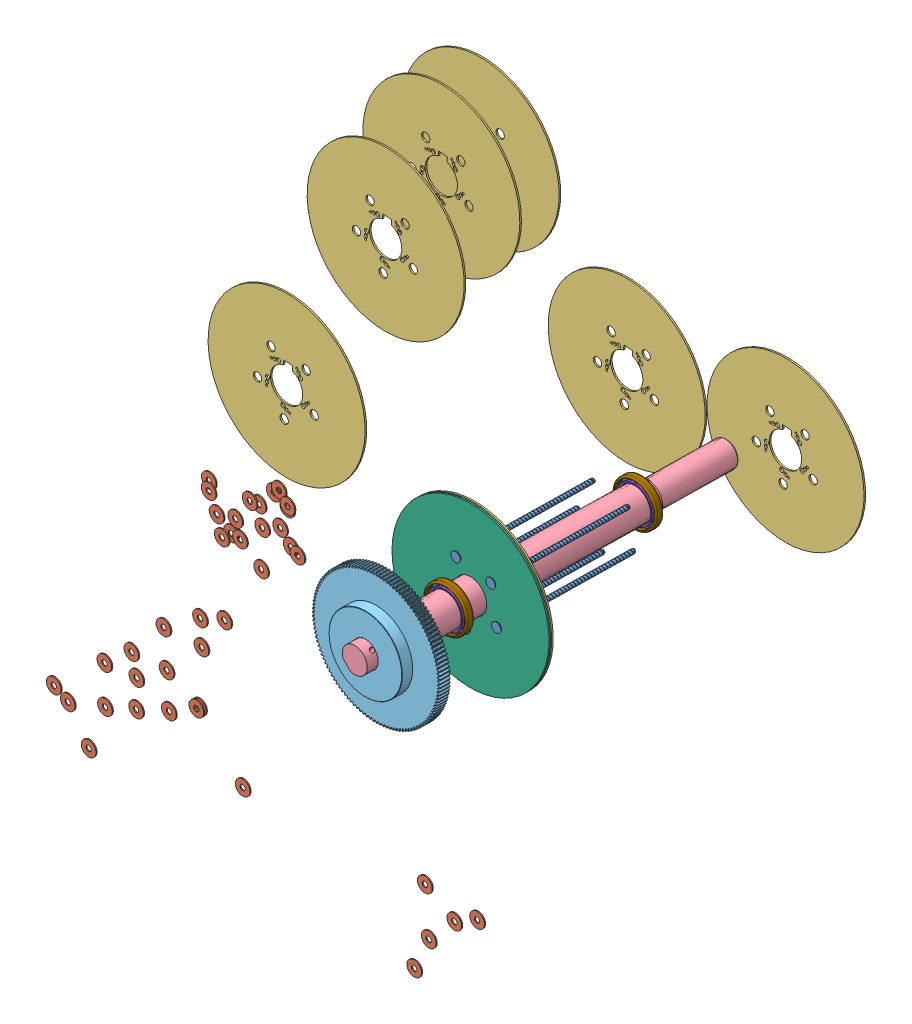
SolidWorks assembly Assemblage1, configuration Défaut. Lengths in mm.
Overall size (703.13 570.75 565.38).
85 component instances, 10 part files, 35 mates.
Components (placement in the parent):
- VISSE-1: VISSE [Défaut] at (277.8026 424.0876 541.0643) x (0.216681 0.976212 -0.007773) z (0.007976 -0.009732 -0.999921) size (9 9 132.7)
- rondelle-1: rondelle [Défaut] at (-148.9296 99.1333 254.7745) x (0.999968 0.00006 0.007975) z (-0.007976 0.009732 0.999921) size (14 14 1)
- VISSE-2: VISSE [Défaut] at (331.7467 416.4054 541.5693) x (-0.90111 0.433439 -0.011406) z (0.007976 -0.009732 -0.999921) size (9 9 132.7)
- VISSE-3: VISSE [Défaut] at (292.6231 454.3278 540.8882) x (-0.532627 -0.846341 0.003989) z (0.007976 -0.009732 -0.999921) size (9 9 132.7)
- VISSE-4: VISSE [Défaut] at (301.9855 400.6464 541.0921) x (-0.532627 -0.846341 0.003989) z (0.007976 -0.009732 -0.999921) size (9 9 132.7)
- VISSE-5: VISSE [Défaut] at (325.9623 449.5799 541.2003) x (-0.532627 -0.846341 0.003989) z (0.007976 -0.009732 -0.999921) size (9 9 132.7)
- rondelle-2: rondelle [Défaut] at (-118.629 125.1433 313.0588) x (0.999968 0.00006 0.007975) z (-0.007976 0.009732 0.999921) size (14 14 1)
- rondelle-3: rondelle [Défaut] at (-182.4235 150.5363 299.0279) x (0.999968 0.00006 0.007975) z (-0.007976 0.009732 0.999921) size (14 14 1)
- rondelle-4: rondelle [Défaut] at (-119.0756 118.7045 278.1482) x (0.999968 0.00006 0.007975) z (-0.007976 0.009732 0.999921) size (14 14 1)
- rondelle-5: rondelle [Défaut] at (-146.2212 130.9904 284.4457) x (0.999968 0.00006 0.007975) z (-0.007976 0.009732 0.999921) size (14 14 1)
- DISQUE ALLU+ OUIE VENTILL-1: DISQUE ALLU+ OUIE VENTILL [Défaut] at (-167.3503 288.2603 145.7613) x (0.997413 -0.071368 0.00865) z (-0.007976 0.009732 0.999921) size (150 167.56 1.5)
- rondelle-6: rondelle [Défaut] at (-162.6889 138.0928 257.0546) x (0.999968 0.000092 0.007975) z (-0.007976 0.009732 0.999921) size (14 14 1)
- rondelle-11: rondelle [Défaut] at (-148.3959 140.1965 320.5905) x (0.999968 0.00006 0.007975) z (-0.007976 0.009732 0.999921) size (14 14 1)
- rondelle-12: rondelle [Défaut] at (-133.694 149.4021 272.9941) x (0.999968 0.00006 0.007975) z (-0.007976 0.009732 0.999921) size (14 14 1)
- rondelle-13: rondelle [Défaut] at (-139.8547 157.5635 316.3507) x (0.999968 0.00006 0.007975) z (-0.007976 0.009732 0.999921) size (14 14 1)
- rondelle-14: rondelle [Défaut] at (-192.9519 148.4735 288.2823) x (0.999968 0.00006 0.007975) z (-0.007976 0.009732 0.999921) size (14 14 1)
- DISQUE ALLU+ OUIE VENTILL-2: DISQUE ALLU+ OUIE VENTILL [Défaut] at (-137.7877 346.5712 85.3276) x (0.997413 -0.071368 0.00865) z (-0.007976 0.009732 0.999921) size (150 167.56 1.5)
- rondelle-15: rondelle [Défaut] at (-76.3686 131.5662 411.858) x (0.999968 0.00006 0.007975) z (-0.007976 0.009732 0.999921) size (14 14 1)
- rondelle-16: rondelle [Défaut] at (302.0105 400.6159 537.9604) x (0.999968 0.00006 0.007975) z (-0.007976 0.009732 0.999921) size (14 14 1)
- rondelle-17: rondelle [Défaut] at (331.7748 416.371 538.0445) x (0.202872 -0.979142 0.011148) z (-0.007976 0.009732 0.999921) size (14 14 1)
- rondelle-18: rondelle [Défaut] at (277.8307 424.0533 537.5394) x (0.999968 0.00006 0.007975) z (-0.007976 0.009732 0.999921) size (14 14 1)
- rondelle-19: rondelle [Défaut] at (-147.753 152.4645 267.1245) x (0.999968 0.00006 0.007975) z (-0.007976 0.009732 0.999921) size (14 14 1)
- DISQUE ALLU+ OUIE VENTILL-3: DISQUE ALLU+ OUIE VENTILL [Défaut] at (306.0635 428.9613 536.2167) x (-0.717987 0.695944 -0.0125) z (-0.007976 0.009732 0.999921) size (150 167.56 1.5)
- rondelle-20: rondelle [Défaut] at (-141.1296 164.093 301.4144) x (0.999968 0.00006 0.007975) z (-0.007976 0.009732 0.999921) size (14 14 1)
- rondelle-21: rondelle [Défaut] at (-64.5845 154.72 402.0282) x (0.999968 0.00006 0.007975) z (-0.007976 0.009732 0.999921) size (14 14 1)
- rondelle-22: rondelle [Défaut] at (-22.2677 51.0574 426.8322) x (0.999968 0.00006 0.007975) z (-0.007976 0.009732 0.999921) size (14 14 1)
- rondelle-23: rondelle [Défaut] at (-116.7122 87.9334 462.9733) x (0.999968 0.00006 0.007975) z (-0.007976 0.009732 0.999921) size (14 14 1)
- rondelle-24: rondelle [Défaut] at (-103.287 134.0122 451.4069) x (0.999968 0.00006 0.007975) z (-0.007976 0.009732 0.999921) size (14 14 1)
- rondelle-25: rondelle [Défaut] at (-61.4425 98.7216 431.652) x (0.999968 0.00006 0.007975) z (-0.007976 0.009732 0.999921) size (14 14 1)
- rondelle-26: rondelle [Défaut] at (-108.361 134.061 415.9103) x (0.999968 0.00006 0.007975) z (-0.007976 0.009732 0.999921) size (14 14 1)
- rondelle-27: rondelle [Défaut] at (-88.1313 117.5099 433.1686) x (0.999968 0.00006 0.007975) z (-0.007976 0.009732 0.999921) size (14 14 1)
- rondelle-28: rondelle [Défaut] at (-135.2254 105.9348 444.9949) x (0.999968 0.00006 0.007975) z (-0.007976 0.009732 0.999921) size (14 14 1)
- rondelle-29: rondelle [Défaut] at (-151.1299 147.1104 282.8282) x (0.999968 0.00006 0.007975) z (-0.007976 0.009732 0.999921) size (14 14 1)
- rondelle-30: rondelle [Défaut] at (-61.4226 98.6973 429.1522) x (0.999968 0.00006 0.007975) z (-0.007976 0.009732 0.999921) size (14 14 1)
- rondelle-31: rondelle [Défaut] at (-90.0117 80.8982 429.0974) x (0.999968 0.00006 0.007975) z (-0.007976 0.009732 0.999921) size (14 14 1)
- rondelle-32: rondelle [Défaut] at (-94.5971 137.8706 394.9955) x (0.999968 0.00006 0.007975) z (-0.007976 0.009732 0.999921) size (14 14 1)
- rondelle-33: rondelle [Défaut] at (-103.6843 110.0074 446.2364) x (0.999968 0.00006 0.007975) z (-0.007976 0.009732 0.999921) size (14 14 1)
- rondelle-34: rondelle [Défaut] at (-109.7884 78.1412 440.3552) x (0.999968 0.00006 0.007975) z (-0.007976 0.009732 0.999921) size (14 14 1)
- rondelle-35: rondelle [Défaut] at (325.9905 449.5456 537.6755) x (0.578451 0.81571 -0.003325) z (-0.007976 0.009732 0.999921) size (14 14 1)
- rondelle-36: rondelle [Défaut] at (292.6512 454.2935 537.3633) x (0.591401 -0.806279 0.012564) z (-0.007976 0.009732 0.999921) size (14 14 1)
- rondelle-37: rondelle [Défaut] at (-111.457 114.9064 503.537) x (0.999968 0.00006 0.007975) z (-0.007976 0.009732 0.999921) size (14 14 1)
- rondelle-38: rondelle [Défaut] at (-106.9384 71.5744 488.1893) x (0.999968 0.00006 0.007975) z (-0.007976 0.009732 0.999921) size (14 14 1)
- rondelle-39: rondelle [Défaut] at (-131.1185 115.485 497.0836) x (0.999968 0.00006 0.007975) z (-0.007976 0.009732 0.999921) size (14 14 1)
- DISQUE ALLU+ OUIE VENTILL-4: DISQUE ALLU+ OUIE VENTILL [Défaut] at (51.9448 285.7033 136.5749) x (0.997413 -0.071368 0.00865) z (-0.007976 0.009732 0.999921) size (150 167.56 1.5)
- DISQUE ALLU+ OUIE VENTILL-5: DISQUE ALLU+ OUIE VENTILL [Défaut] at (291.9253 385.0126 226.0248) x (0.997413 -0.071368 0.00865) z (-0.007976 0.009732 0.999921) size (150 167.56 1.5)
- DISQUE ALLU+ OUIE VENTILL-6: DISQUE ALLU+ OUIE VENTILL [Défaut] at (-197.363 185.3016 209.6416) x (0.997413 -0.071368 0.00865) z (-0.007976 0.009732 0.999921) size (150 167.56 1.5)
- DISQUE ALLU+ OUIE VENTILL-7: DISQUE ALLU+ OUIE VENTILL [Défaut] at (-148.1879 332.7086 112.1514) x (0.997413 -0.071368 0.00865) z (-0.007976 0.009732 0.999921) size (150 167.56 1.5)
- rondelle-40: rondelle [Défaut] at (-129.5914 139.1392 284.0742) x (0.999968 0.000039 0.007976) z (-0.007976 0.009732 0.999921) size (14 14 1)
- rondelle-41: rondelle [Défaut] at (-147.0823 134.3101 259.8209) x (0.999968 0.000039 0.007976) z (-0.007976 0.009732 0.999921) size (14 14 1)
- rondelle-42: rondelle [Défaut] at (-154.5135 132.9847 305.7182) x (0.999968 0.000039 0.007976) z (-0.007976 0.009732 0.999921) size (14 14 1)
- rondelle-43: rondelle [Défaut] at (-172.0385 137.9139 301.8567) x (0.999968 0.000039 0.007976) z (-0.007976 0.009732 0.999921) size (14 14 1)
- rondelle-44: rondelle [Défaut] at (-133.6882 144.6052 318.0122) x (0.999968 0.000039 0.007976) z (-0.007976 0.009732 0.999921) size (14 14 1)
- rondelle-45: rondelle [Défaut] at (102.5071 10.0469 378.991) size (14 14 1)
- rondelle-46: rondelle [Défaut] at (133.9044 -3.0744 382.4627) size (14 14 1)
- rondelle-47: rondelle [Défaut] at (131.3912 -8.0815 404.1275) size (14 14 1)
- rondelle-48: rondelle [Défaut] at (140.317 -16.0974 426.83) size (14 14 1)
- rondelle-49: rondelle [Défaut] at (-81.7374 49.4513 214.4173) size (14 14 1)
- rondelle-50: rondelle [Défaut] at (139.2307 -7.242 366.1613) size (14 14 1)
- ARBRE MECANIQUE-2: ARBRE MECANIQUE [Défaut] at (306.5593 428.3563 474.0602) x (-0.717987 0.695944 -0.0125) z (-0.007976 0.009732 0.999921) size (47 47 350)
- Engrenage turbine-1: Engrenage turbine [Default] at (305.4028 429.7675 619.0488) x (-0.717987 0.695944 -0.0125) z (-0.007976 0.009732 0.999921) size (122 122 22.79)
- DISQUE ALLU-1: DISQUE ALLU [Défaut] at (306.0435 428.9856 538.7165) x (-0.717987 0.695944 -0.0125) z (-0.007976 0.009732 0.999921) size (150 191.7 1.5)
- CLAVETTE-1: CLAVETTE [Défaut] at (290.765 416.8826 432.4586) x (-0.007976 0.009732 0.999921) z (0.696011 0.71803 -0.001437) size (40 8 7)
- CLAVETTE-2: CLAVETTE [Défaut] at (295.6375 421.9083 432.3975) x (0.007976 -0.009732 -0.999921) z (-0.696011 -0.71803 0.001437) size (40 8 7)
- Assemblage roulement-1: Assemblage roulement [Défaut] at (429.0565 385.4719 436.5298) x (0.007976 -0.009732 -0.999921) z (0.999921 -0.009654 0.00807) size (7 58.99 58.99)
  - Bague roulement interieur-1: Bague roulement interieur [Défaut] at (-125.7423 41.326 -122.5987) size (7 34 34)
  - Bague roulement exterieur-1: Bague roulement exterieur [Défaut] at (-125.7423 41.326 -122.5987) x (1 0 0) z (0 -0.620077 0.784541) size (7 42 42)
  - bille roulement-10: bille roulement [Défaut] at (-125.7423 24.196 -122.5987) size (4.26 4.26 4.26)
  - bille roulement-11: bille roulement [Défaut] at (-125.7423 29.2133 -110.486) x (1 0 0) z (0 0.707107 0.707107) size (4.26 4.26 4.26)
  - bille roulement-12: bille roulement [Défaut] at (-125.7423 41.326 -105.4687) x (1 0 0) z (0 1 0) size (4.26 4.26 4.26)
  - bille roulement-13: bille roulement [Défaut] at (-125.7423 53.4387 -110.486) x (1 0 0) z (0 0.707107 -0.707107) size (4.26 4.26 4.26)
  - bille roulement-14: bille roulement [Défaut] at (-125.7423 58.456 -122.5987) x (1 0 0) z (0 0 -1) size (4.26 4.26 4.26)
  - bille roulement-15: bille roulement [Défaut] at (-125.7423 53.4387 -134.7115) x (1 0 0) z (0 -0.707107 -0.707107) size (4.26 4.26 4.26)
  - bille roulement-16: bille roulement [Défaut] at (-125.7423 41.326 -139.7287) x (1 0 0) z (0 -1 0) size (4.26 4.26 4.26)
  - bille roulement-17: bille roulement [Défaut] at (-125.7423 29.2133 -134.7115) x (1 0 0) z (0 -0.707107 0.707107) size (4.26 4.26 4.26)
- Assemblage roulement-2: Assemblage roulement [Défaut] at (430.4768 383.7389 258.4689) x (0.007976 -0.009732 -0.999921) z (0.999921 -0.009654 0.00807) size (7 58.99 58.99)
  - Bague roulement interieur-1: Bague roulement interieur [Défaut] at (-125.7423 41.326 -122.5987) size (7 34 34)
  - Bague roulement exterieur-1: Bague roulement exterieur [Défaut] at (-125.7423 41.326 -122.5987) x (1 0 0) z (0 -0.620077 0.784541) size (7 42 42)
  - bille roulement-10: bille roulement [Défaut] at (-125.7423 24.196 -122.5987) size (4.26 4.26 4.26)
  - bille roulement-11: bille roulement [Défaut] at (-125.7423 29.2133 -110.486) x (1 0 0) z (0 0.707107 0.707107) size (4.26 4.26 4.26)
  - bille roulement-12: bille roulement [Défaut] at (-125.7423 41.326 -105.4687) x (1 0 0) z (0 1 0) size (4.26 4.26 4.26)
  - bille roulement-13: bille roulement [Défaut] at (-125.7423 53.4387 -110.486) x (1 0 0) z (0 0.707107 -0.707107) size (4.26 4.26 4.26)
  - bille roulement-14: bille roulement [Défaut] at (-125.7423 58.456 -122.5987) x (1 0 0) z (0 0 -1) size (4.26 4.26 4.26)
  - bille roulement-15: bille roulement [Défaut] at (-125.7423 53.4387 -134.7115) x (1 0 0) z (0 -0.707107 -0.707107) size (4.26 4.26 4.26)
  - bille roulement-16: bille roulement [Défaut] at (-125.7423 41.326 -139.7287) x (1 0 0) z (0 -1 0) size (4.26 4.26 4.26)
  - bille roulement-17: bille roulement [Défaut] at (-125.7423 29.2133 -134.7115) x (1 0 0) z (0 -0.707107 0.707107) size (4.26 4.26 4.26)
Mates (geometry in assembly coordinates):
- Coaxiale64: concentric anti-aligned: cylinder of ARBRE MECANIQUE-2 through (307.955 426.6533 299.0741) axis (-0.007976 0.009732 0.999921) radius 11.975; cylinder of Engrenage turbine-1 through (305.4028 429.7675 619.0488) axis (0.007976 -0.009732 -0.999921) radius 12
- Parallèle1: parallel anti-aligned: cylinder of ARBRE MECANIQUE-2 through (294.7646 419.1878 641.0686) axis (0.696011 0.71803 -0.001437) radius 2.07; cylinder of Engrenage turbine-1 through (280.9228 404.7824 634.0979) axis (-0.696011 -0.71803 0.001437) radius 2.067
- Coïncidente102: coincident anti-aligned: plane of ARBRE MECANIQUE-2 through (305.4028 429.7675 619.0488) normal (-0.007976 0.009732 0.999921); plane of Engrenage turbine-1 through (263.6422 386.6856 619.135) normal (0.007976 -0.009732 -0.999921)
- Coaxiale72: concentric anti-aligned: cylinder of VISSE-5 through (326.9992 448.3148 411.2106) axis (-0.007976 0.009732 0.999921) radius 2; cone of DISQUE ALLU-1 through (325.98 449.5584 538.9836) axis (0.007976 -0.009732 -0.999921)
- Coaxiale73: concentric anti-aligned: cylinder of VISSE-3 through (293.6599 453.0627 410.8985) axis (-0.007976 0.009732 0.999921) radius 2; cone of DISQUE ALLU-1 through (292.6407 454.3062 538.6715) axis (0.007976 -0.009732 -0.999921)
- Coaxiale75: concentric anti-aligned: cylinder of VISSE-1 through (278.8394 422.8225 411.0746) axis (-0.007976 0.009732 0.999921) radius 2; cone of DISQUE ALLU-1 through (277.8203 424.066 538.8476) axis (0.007976 -0.009732 -0.999921)
- Coaxiale76: concentric anti-aligned: cylinder of VISSE-2 through (332.7835 415.1402 411.5796) axis (-0.007976 0.009732 0.999921) radius 2; cone of DISQUE ALLU-1 through (331.7644 416.3838 539.3526) axis (0.007976 -0.009732 -0.999921)
- Coaxiale77: concentric anti-aligned: cylinder of VISSE-4 through (303.0223 399.3813 411.1024) axis (-0.007976 0.009732 0.999921) radius 2; cylinder of DISQUE ALLU-1 through (301.9905 400.6403 540.4602) axis (0.007976 -0.009732 -0.999921) radius 3
- Coïncidente112: coincident: cone of VISSE-4 through (302.0094 400.6172 538.0924) axis (0.007976 -0.009732 -0.999921); circle of DISQUE ALLU-1
- Coïncidente113: coincident: cone of VISSE-2 through (331.7706 416.3762 538.5696) axis (0.007976 -0.009732 -0.999921); circle of DISQUE ALLU-1
- Coïncidente114: coincident: cone of VISSE-1 through (277.8265 424.0584 538.0645) axis (0.007976 -0.009732 -0.999921); circle of DISQUE ALLU-1
- Coïncidente115: coincident: cone of VISSE-3 through (292.647 454.2986 537.8884) axis (0.007976 -0.009732 -0.999921); circle of DISQUE ALLU-1
- Coïncidente116: coincident: cone of VISSE-5 through (325.9863 449.5507 538.2006) axis (0.007976 -0.009732 -0.999921); circle of DISQUE ALLU-1
- Coaxiale78: concentric anti-aligned: cylinder of ARBRE MECANIQUE-2 through (307.3568 427.3832 374.0681) axis (-0.007976 0.009732 0.999921) radius 15; cylinder of DISQUE ALLU-1 through (306.0316 429.0002 540.2164) axis (0.007976 -0.009732 -0.999921) radius 15.5
- Parallèle9: parallel aligned: plane of ARBRE MECANIQUE-2 through (300.2809 414.1572 374.1404) normal (-0.717987 0.695944 -0.0125); plane of DISQUE ALLU-1 through (298.7083 415.3395 540.291) normal (-0.717987 0.695944 -0.0125)
- Coaxiale79: concentric anti-aligned: cylinder of VISSE-4 through (303.0223 399.3813 411.1024) axis (-0.007976 0.009732 0.999921) radius 2; cylinder of rondelle-16 through (302.0025 400.6257 538.9603) axis (0.007976 -0.009732 -0.999921) radius 2.5
- Coïncidente118: coincident anti-aligned: plane of rondelle-16 through (302.0025 400.6257 538.9603) normal (-0.007976 0.009732 0.999921); plane of DISQUE ALLU-1 through (306.0435 428.9856 538.7165) normal (0.007976 -0.009732 -0.999921)
- Coaxiale80: concentric anti-aligned: cylinder of VISSE-3 through (293.6599 453.0627 410.8985) axis (-0.007976 0.009732 0.999921) radius 2; cylinder of rondelle-36 through (292.6432 454.3032 538.3632) axis (0.007976 -0.009732 -0.999921) radius 2.5
- Coaxiale82: concentric anti-aligned: cylinder of VISSE-1 through (278.8394 422.8225 411.0746) axis (-0.007976 0.009732 0.999921) radius 2; cylinder of rondelle-18 through (277.8228 424.063 538.5393) axis (0.007976 -0.009732 -0.999921) radius 2.5
- Coaxiale83: concentric anti-aligned: cylinder of VISSE-5 through (326.9992 448.3148 411.2106) axis (-0.007976 0.009732 0.999921) radius 2; cylinder of rondelle-35 through (325.9825 449.5554 538.6754) axis (0.007976 -0.009732 -0.999921) radius 2.5
- Coaxiale84: concentric anti-aligned: cylinder of VISSE-2 through (332.7835 415.1402 411.5796) axis (-0.007976 0.009732 0.999921) radius 2; cylinder of rondelle-17 through (331.7668 416.3808 539.0444) axis (0.007976 -0.009732 -0.999921) radius 2.5
- Coïncidente119: coincident anti-aligned: plane of rondelle-18 through (277.8228 424.063 538.5393) normal (-0.007976 0.009732 0.999921); plane of DISQUE ALLU-1 through (306.0435 428.9856 538.7165) normal (0.007976 -0.009732 -0.999921)
- Coïncidente120: coincident anti-aligned: plane of rondelle-17 through (331.7668 416.3808 539.0444) normal (-0.007976 0.009732 0.999921); plane of DISQUE ALLU-1 through (306.0435 428.9856 538.7165) normal (0.007976 -0.009732 -0.999921)
- Coïncidente121: coincident anti-aligned: plane of rondelle-35 through (325.9825 449.5554 538.6754) normal (-0.007976 0.009732 0.999921); plane of DISQUE ALLU-1 through (306.0435 428.9856 538.7165) normal (0.007976 -0.009732 -0.999921)
- Coïncidente122: coincident anti-aligned: plane of rondelle-36 through (292.6432 454.3032 538.3632) normal (-0.007976 0.009732 0.999921); plane of DISQUE ALLU-1 through (306.0435 428.9856 538.7165) normal (0.007976 -0.009732 -0.999921)
- Coïncidente125: coincident aligned: line of ARBRE MECANIQUE-2 through (301.6675 415.9917 396.6354) axis (-0.007976 0.009732 0.999921); line of CLAVETTE-1 through (301.6681 415.9909 396.5514) axis (-0.007976 0.009732 0.999921)
- Verrouiller2: lock: unknown of ?; unknown of ?
- Parallèle16: parallel anti-aligned: plane of ARBRE MECANIQUE-2 through (300.2809 414.1572 374.1404) normal (-0.717987 0.695944 -0.0125); plane of CLAVETTE-2 through (296.5093 411.3146 432.5076) normal (0.717987 -0.695944 0.0125)
- Coïncidente129: coincident anti-aligned: line of ARBRE MECANIQUE-2 through (301.6675 415.9917 396.6354) axis (-0.007976 0.009732 0.999921); line of CLAVETTE-2 through (301.0943 416.6911 468.4947) axis (0.007976 -0.009732 -0.999921)
- Verrouiller3: lock: unknown of ?; unknown of ?
- Coaxiale85: concentric aligned: cylinder of ARBRE MECANIQUE-2 through (307.3568 427.3832 374.0681) axis (-0.007976 0.009732 0.999921) radius 15; cylinder of Assemblage roulement-1/Bague roulement interieur-1 through (305.5014 429.6472 606.692) axis (-0.007976 0.009732 0.999921) radius 15
- Coaxiale86: concentric aligned: cylinder of ARBRE MECANIQUE-2 through (307.3568 427.3832 374.0681) axis (-0.007976 0.009732 0.999921) radius 15; cylinder of Assemblage roulement-2/Bague roulement interieur-1 through (306.9216 427.9142 428.6311) axis (-0.007976 0.009732 0.999921) radius 15
- Parallèle21: parallel anti-aligned: plane of DISQUE ALLU+ OUIE VENTILL-3 through (295.7702 412.2636 537.7973) normal (0.696011 0.71803 -0.001437); plane of CLAVETTE-1 through (290.765 416.8826 432.4586) normal (-0.696011 -0.71803 0.001437)
- Coaxiale88: concentric anti-aligned: cylinder of DISQUE ALLU+ OUIE VENTILL-3 through (306.0515 428.9759 537.7166) axis (0.007976 -0.009732 -0.999921) radius 15.5; cylinder of ARBRE MECANIQUE-2 through (307.955 426.6533 299.0741) axis (-0.007976 0.009732 0.999921) radius 11.975
- Coïncidente134: coincident anti-aligned: plane of rondelle-16 through (302.0105 400.6159 537.9604) normal (0.007976 -0.009732 -0.999921); plane of DISQUE ALLU+ OUIE VENTILL-3 through (306.0515 428.9759 537.7166) normal (-0.007976 0.009732 0.999921)
